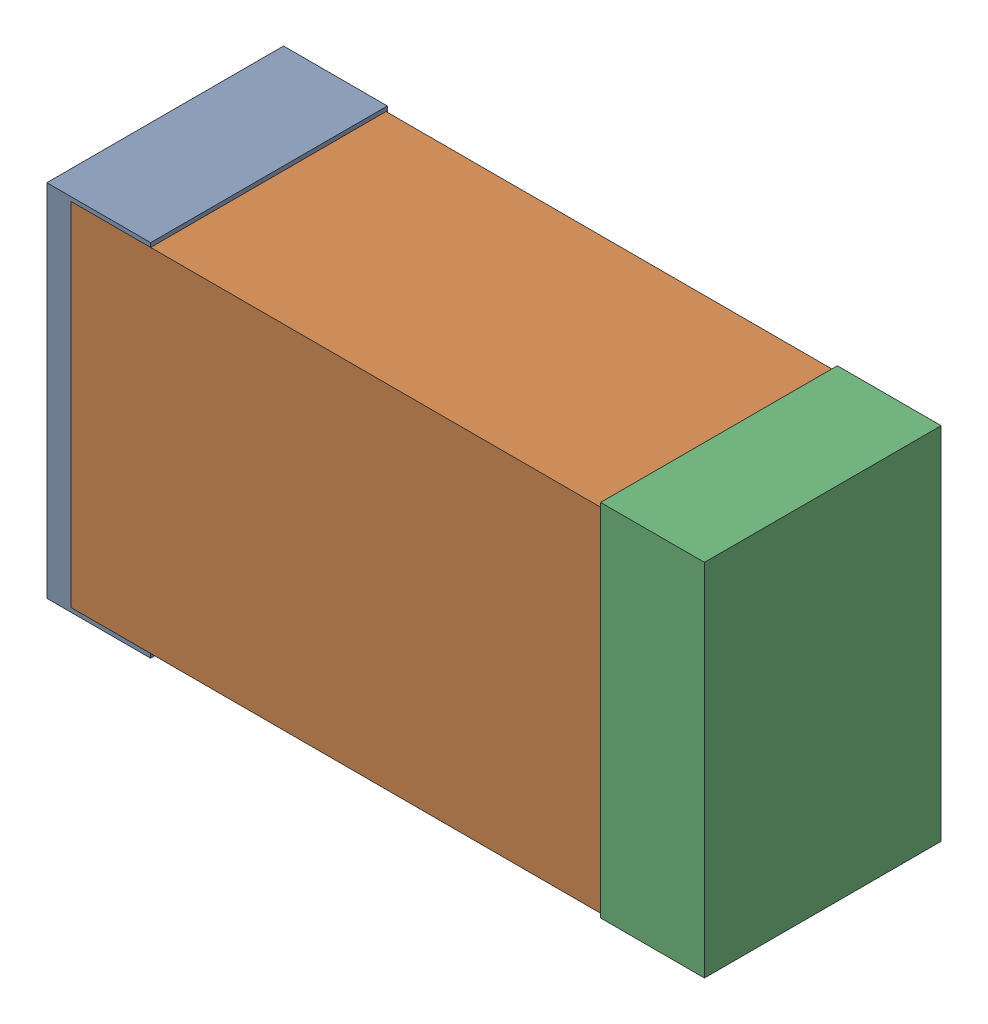
SolidWorks assembly USB45_C11, configuration Default. Lengths in mm.
Overall size (2.38 1.3 0.85).
6 component instances, 2 part files, 0 mates.
Components (placement in the parent):
- 384311232-1: 384311232 [Default] at (172.99 37.719 -1.9574) size (0.38 1.3 0.85)
  - Extruded_8-1: Extruded_8 [Default] at origin size (0.38 1.3 0.85)
- 384311360-1: 384311360 [Default] at (173.99 37.719 -1.9524) size (2.2 1.27 0.85)
  - Extruded_9-1: Extruded_9 [Default] at origin size (2.2 1.27 0.85)
- 384311232-2: 384311232 [Default] at (174.99 37.719 -1.9574) size (0.38 1.3 0.85)
  - Extruded_8-1: Extruded_8 [Default] at origin size (0.38 1.3 0.85)
